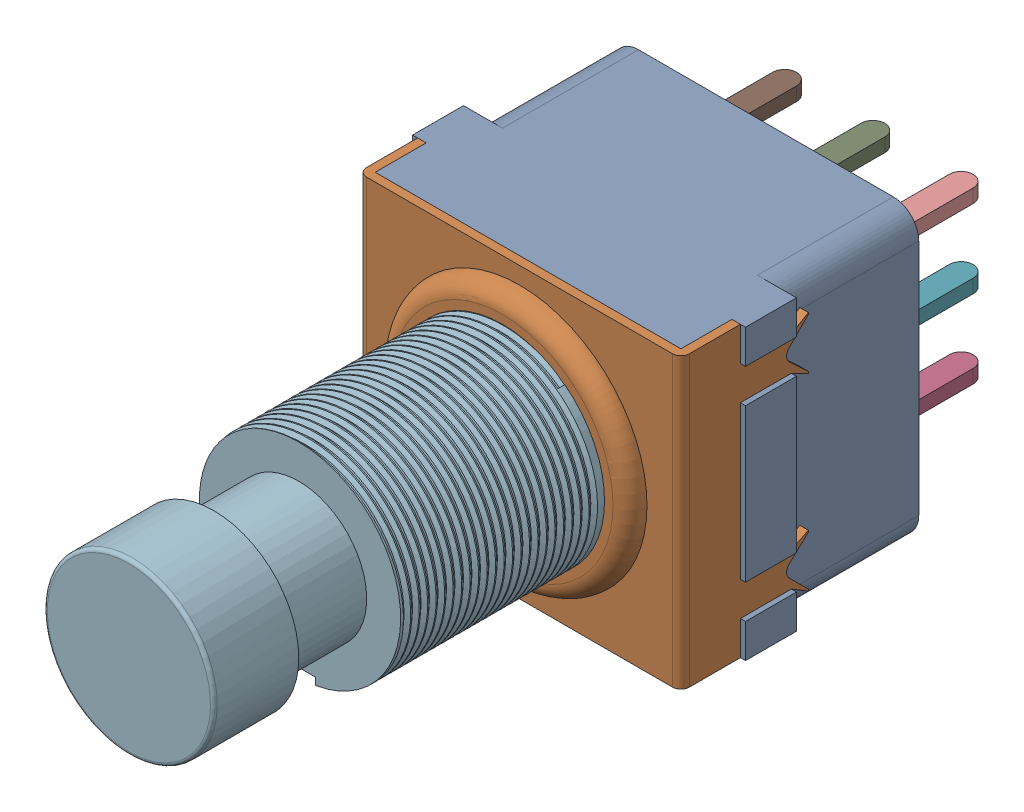
SolidWorks assembly 3PDT, configuration Default. Lengths in mm.
Overall size (19.6 17 44.5).
12 component instances, 4 part files, 0 mates.
Components (placement in the parent):
- 3PDT Body-1: 3PDT Body [Default] at (0 -2.1806 0.7727) size (19.6 17 15)
- 3PDT Cover-1: 3PDT Cover [Default] at (-0.5 14.8194 11.7727) x (1 0 0) z (0 -1 0) size (19 8.5 17)
- 3PDT Pin-1: 3PDT Pin [Default] at (7 1.7194 0.7727) x (1 0 0) z (0 1 0) size (4 7 0.8)
- 3PDT Pin-2: 3PDT Pin [Default] at (12.2 1.7194 0.7727) x (1 0 0) z (0 1 0) size (4 7 0.8)
- 3PDT Pin-3: 3PDT Pin [Default] at (1.8 1.7194 0.7727) x (1 0 0) z (0 1 0) size (4 7 0.8)
- 3PDT Pin-4: 3PDT Pin [Default] at (7 6.3194 0.7727) x (1 0 0) z (0 1 0) size (4 7 0.8)
- 3PDT Pin-5: 3PDT Pin [Default] at (12.2 6.3194 0.7727) x (1 0 0) z (0 1 0) size (4 7 0.8)
- 3PDT Pin-6: 3PDT Pin [Default] at (1.8 6.3194 0.7727) x (1 0 0) z (0 1 0) size (4 7 0.8)
- 3PDT Pin-7: 3PDT Pin [Default] at (7 10.9194 0.7727) x (1 0 0) z (0 1 0) size (4 7 0.8)
- 3PDT Pin-8: 3PDT Pin [Default] at (12.2 10.9194 0.7727) x (1 0 0) z (0 1 0) size (4 7 0.8)
- 3PDT Pin-9: 3PDT Pin [Default] at (1.8 10.9194 0.7727) x (1 0 0) z (0 1 0) size (4 7 0.8)
- 3PDT Schalter-1: 3PDT Schalter [Default] at (9 6.3194 28.2727) x (0 -1 0) z (0 0 1) size (12 12.17 22.2)
